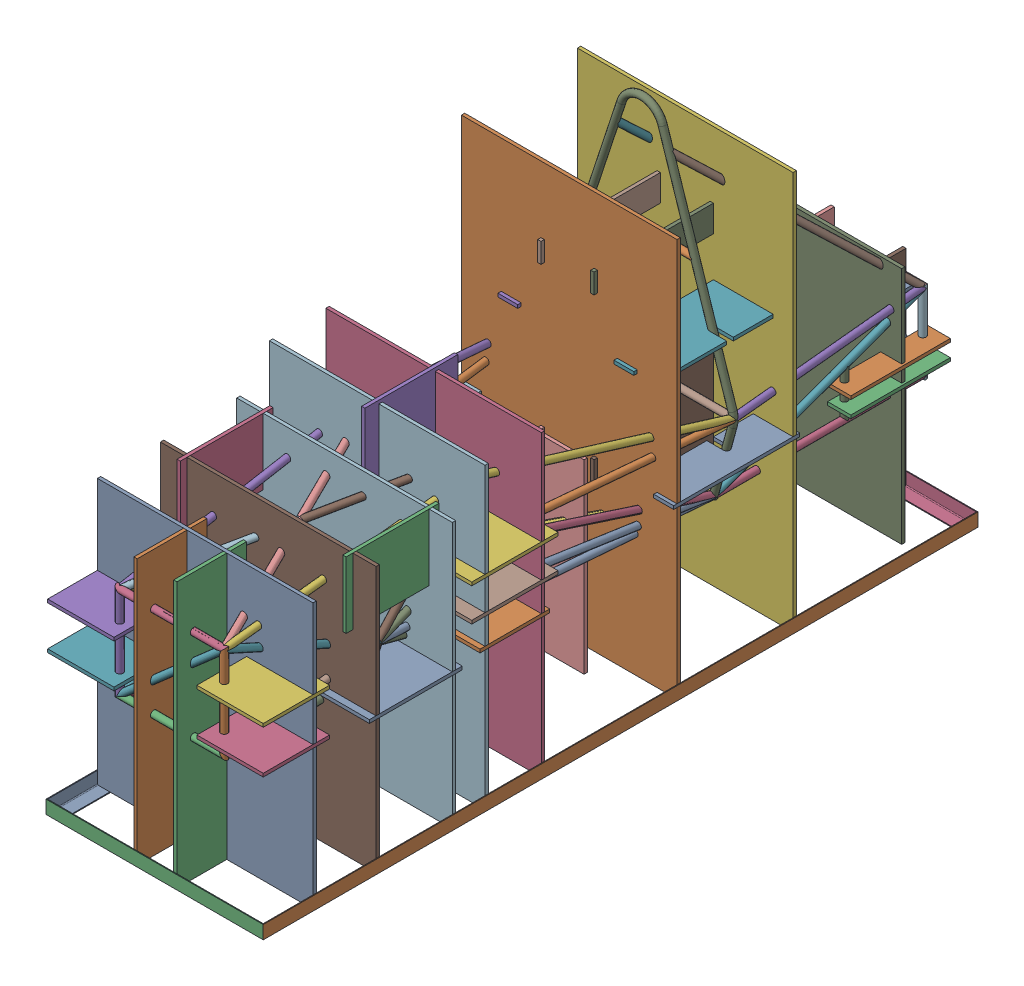
SolidWorks assembly Jig Table Assembly, configuration Default. Lengths in mm.
Overall size (831.85 1671.03 2736.85).
6 component instances, 3 part files, 3 mates.
Components (placement in the parent):
- Jig Table_001-1: Jig Table_001 [Default] at origin size (831.85 50.8 2736.85)
  - 2inx0.125in_angle iron_107.75in-1: 2inx0.125in_angle iron_107.75in [8968K586] at origin size (50.8 50.8 2736.85)
  - 2inx0.125in_angle iron_107.75in-2: 2inx0.125in_angle iron_107.75in [8968K586] at (781.05 0 0) x (-1 0 0) z (0 0 -1) size (50.8 50.8 2736.85)
  - 2inx0.125in_angle iron_32.75in-3: 2inx0.125in_angle iron_32.75in [8968K586] at (390.525 0 1343.025) x (0 0 -1) z (1 0 0) size (50.8 50.8 831.85)
  - 2inx0.125in_angle iron_32.75in-4: 2inx0.125in_angle iron_32.75in [8968K586] at (390.525 0 -1343.025) x (0 0 1) z (-1 0 0) size (50.8 50.8 831.85)
- Jig_Assembly_001_Part-1: Jig_Assembly_001_Part [Default] at (390.525 447.675 1301.75) x (0 0 -1) z (1 0 0) size (2730.5 1667.85 825.5)
Mates (geometry in assembly coordinates):
- Coincident1: coincident: plane of Jig Table_001-1/8968K586_Zinc-Galvanized Low-Carbon Steel 90 Degree Angle_3-3 through (-25.4 -22.225 1317.625) normal (0 1 0); plane of Jig_Assembly_001_Part-1 through (473.075 -22.225 1338.4361) normal (0 -1 0)
- Coincident2: coincident: plane of Jig Table_001-1/8968K586_Zinc-Galvanized Low-Carbon Steel 90 Degree Angle_6-2 through (803.275 -18.8383 1368.425) normal (-1 0 0); plane of Jig_Assembly_001_Part-1 through (803.275 -22.225 1135.2361) normal (1 0 0)
- Coincident3: coincident anti-aligned: plane of Jig Table_001-1/8968K586_Zinc-Galvanized Low-Carbon Steel 90 Degree Angle_3-3 through (-25.4 -18.8383 1365.25) normal (0 0 -1); plane of Jig_Assembly_001_Part-1 through (473.075 -22.225 1338.4361) normal (0 0 1)
